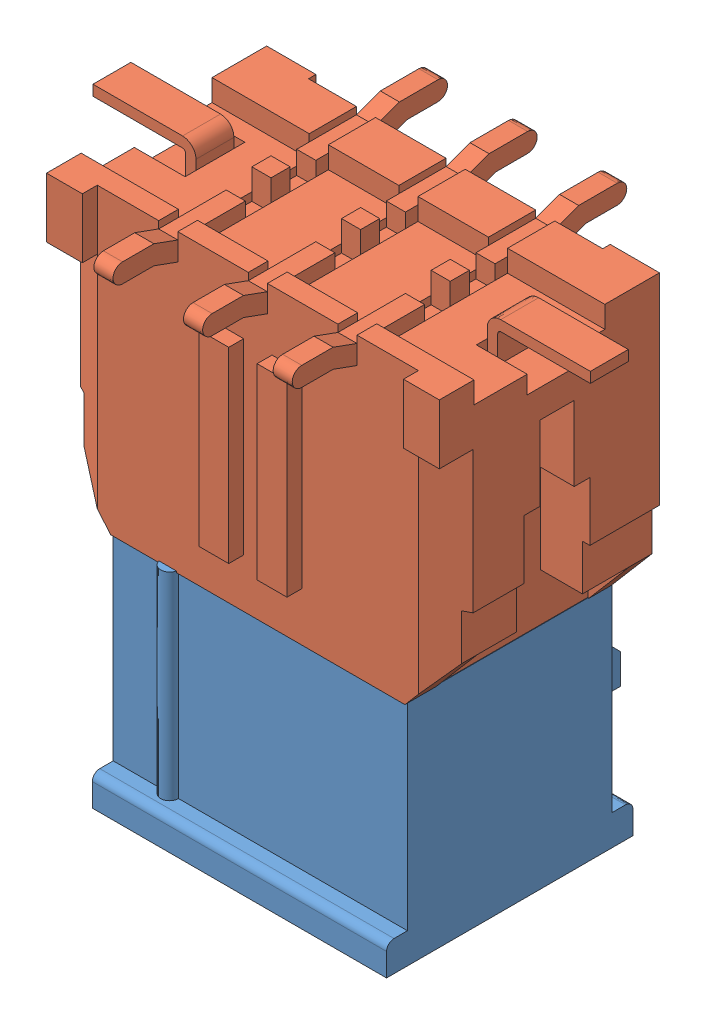
SolidWorks assembly Assem1, configuration Default. Lengths in mm.
Overall size (16.65 17.56 12.37).
2 component instances, 2 part files, 0 mates.
Components (placement in the parent):
- Part4-1: Part4 [Default] at (9.1728 3.5568 10.46) size (9.85 14 10.83)
- 430450618-1: 430450618 [Default] at (9.1519 12.1065 10.5166) x (-1 0 0) z (0 -1 0) size (16.65 11.2 9.96)
